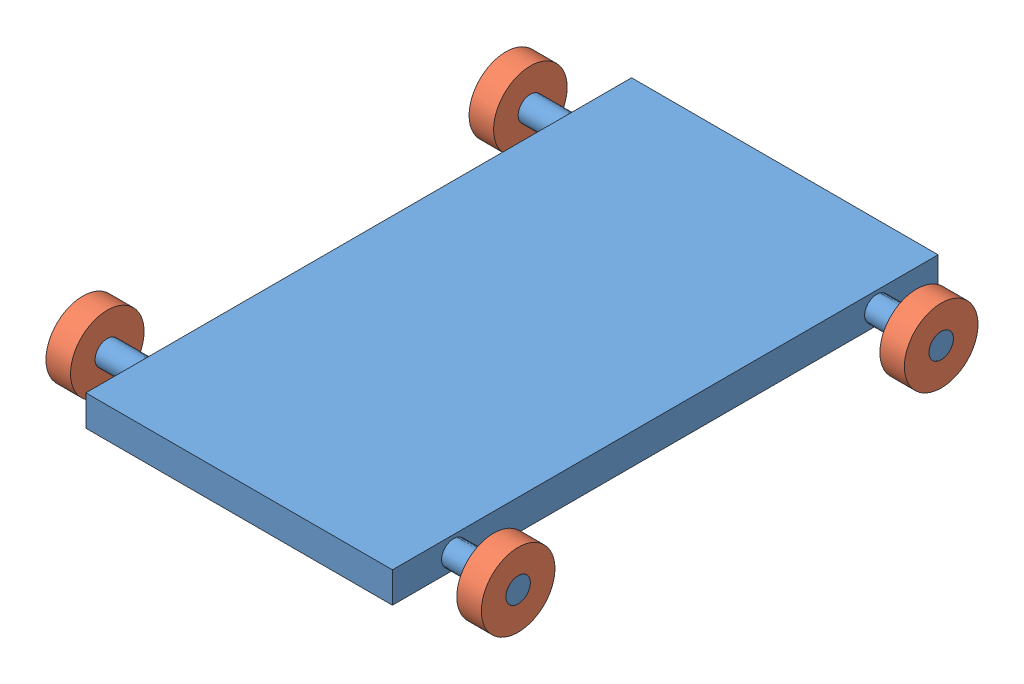
SolidWorks assembly ros_test_assembly, configuration Default. Lengths in mm.
Overall size (710 120 890).
5 component instances, 2 part files, 8 mates.
Components (placement in the parent):
- frame-1: frame [Default] at (171.3913 429.1046 792.0283) size (710 50 890)
- Wheel-1: Wheel [Default] at (506.3913 453.3789 1137.0283) x (0 0 -1) z (1 0 0) size (120 120 40)
- Wheel-2: Wheel [Default] at (506.3913 453.3789 447.0283) x (0 0 -1) z (1 0 0) size (120 120 40)
- Wheel-3: Wheel [Default] at (-163.6087 453.3789 447.0283) x (0 0 -1) z (1 0 0) size (120 120 40)
- Wheel-4: Wheel [Default] at (-163.6087 453.3789 1137.0283) x (0 0 -1) z (1 0 0) size (120 120 40)
Mates (geometry in assembly coordinates):
- Concentric1: concentric anti-aligned: circle of Bottom Frame-1; circle of Fake wheel-1
- Coincident1: coincident aligned: plane of Bottom Frame-1 through (526.3913 453.3789 1137.0283) normal (1 0 0); plane of Fake wheel-1 through (526.3913 453.3789 1137.0283) normal (1 0 0)
- Concentric2: concentric anti-aligned: circle of Bottom Frame-1; circle of Fake wheel-4
- Concentric3: concentric aligned: circle of Bottom Frame-1; circle of Fake wheel-3
- Coincident4: coincident aligned: circle of Bottom Frame-1; circle of Fake wheel-2
- Concentric4: concentric aligned: circle of Bottom Frame-1; circle of Fake wheel-2
- Coincident6: coincident aligned: plane of Bottom Frame-1 through (-183.6087 453.3789 1137.0283) normal (-1 0 0); plane of Fake wheel-4 through (-183.6087 453.3789 1137.0283) normal (-1 0 0)
- Coincident7: coincident aligned: plane of Bottom Frame-1 through (-183.6087 453.3789 447.0283) normal (-1 0 0); plane of Fake wheel-3 through (-183.6087 453.3789 447.0283) normal (-1 0 0)
